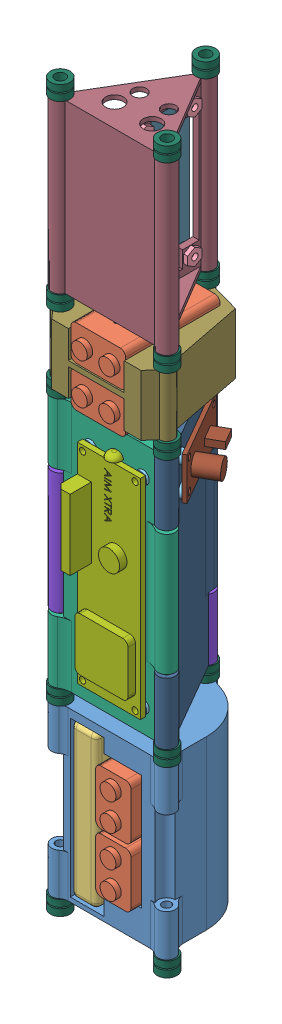
SolidWorks assembly S1B_Electronics_Bay_Avionics_Stack, configuration Default. Lengths in mm.
Overall size (104.18 344.14 103.27).
66 component instances, 15 part files, 28 mates.
Components (placement in the parent):
- S1B_Flight_Power_Stack_Assy-1: S1B_Flight_Power_Stack_Assy [Default] at (-4.2933 16.5157 -11.6983) size (58.99 80 57.67)
  - S1B_Power_Stack-1: S1B_Power_Stack [Default] at (-4.1095 89.1616 81.6309) size (58.99 80 52.18)
  - S1B_9V Battery-1: S1B_9V Battery [Default] at (-5.5953 51.787 105.8736) x (0 0 -1) z (0 -1 0) size (47.57 16.87 26.11)
  - S1B_LiPo_A1-1: S1B_LiPo_A1 [Default] at (-22.7297 11.3191 64.2994) x (0 1 0) z (0 0 -1) size (72.97 12.27 33.73)
  - S1B_9V Battery-2: S1B_9V Battery [Default] at (-5.5953 23.6758 105.8736) x (0 0 -1) z (0 -1 0) size (47.57 16.87 26.11)
- S1B_Fight_Computer_Stack_Assy-1: S1B_Fight_Computer_Stack_Assy [Default] at (37.1119 269.2904 8.8488) x (0.5 0 0.866025) z (0 -1 0) size (74.68 77.18 120)
  - S1B_6.86mm_Nut_3mm_Hole-7: S1B_6.86mm_Nut_3mm_Hole [Default] at (49.4605 62.5264 50.3494) x (0.433013 -0.75 0.5) z (-0.25 0.433013 0.866025) size (7.92 1.91 6.86)
  - S1B_6.86mm_Nut_3mm_Hole-10: S1B_6.86mm_Nut_3mm_Hole [Default] at (38.5881 85.168 145.066) x (-0.433013 0.75 -0.5) z (-0.25 0.433013 0.866025) size (7.92 1.91 6.86)
  - S1B_6.86mm_Nut_3mm_Hole-11: S1B_6.86mm_Nut_3mm_Hole [Default] at (36.9383 84.2155 50.3494) x (0.433013 -0.75 -0.5) z (0.25 -0.433013 0.866025) size (7.92 1.91 6.86)
  - S1B_6.86mm_Nut_3mm_Hole-12: S1B_6.86mm_Nut_3mm_Hole [Default] at (49.4605 62.5264 145.066) x (0.433013 -0.75 -0.5) z (0.25 -0.433013 0.866025) size (7.92 1.91 6.86)
  - S1B_Ruber_Washer_3mm-5: S1B_Ruber_Washer_3mm [Default] at (53.7083 64.9789 145.066) x (-0.5 0.866025 0) z (0 0 1) size (6 1.25 6)
  - S1B_Ruber_Washer_3mm-6: S1B_Ruber_Washer_3mm [Default] at (41.1861 86.668 145.066) x (-0.5 0.866025 0) z (0 0 1) size (6 1.25 6)
  - S1B_Ruber_Washer_3mm-7: S1B_Ruber_Washer_3mm [Default] at (53.7083 64.9789 50.3494) x (-0.5 0.866025 0) z (0 0 1) size (6 1.25 6)
  - S1B_Ruber_Washer_3mm-8: S1B_Ruber_Washer_3mm [Default] at (41.1861 86.668 50.3494) x (-0.5 0.866025 0) z (0 0 1) size (6 1.25 6)
  - S1B_Avionics_Stack - AIM-1: S1B_Avionics_Stack - AIM [Default] at (55.5493 84.6273 26.5774) x (-0.5 -0.866025 0) z (0 0 1) size (33.58 52.18 120)
  - S1B_AimXtra-1: S1B_AimXtra [Default] at (39.9161 88.8677 47.8094) x (0 0 1) z (-0.5 0.866025 0) size (102.34 16.13 30.12)
  - S1B_6.86mm_Nut_3mm_Hole-13: S1B_6.86mm_Nut_3mm_Hole [Default] at (13.2223 66.1787 125.5587) x (0.433013 0.75 -0.5) z (0.25 0.433013 0.866025) size (7.92 1.91 6.86)
  - S1B_6.86mm_Nut_3mm_Hole-14: S1B_6.86mm_Nut_3mm_Hole [Default] at (24.7223 86.0973 125.5587) x (0.433013 0.75 -0.5) z (0.25 0.433013 0.866025) size (7.92 1.91 6.86)
  - S1B_6.86mm_Nut_3mm_Hole-15: S1B_6.86mm_Nut_3mm_Hole [Default] at (13.2223 66.1787 69.0624) x (0.433013 0.75 0.5) z (-0.25 -0.433013 0.866025) size (7.92 1.91 6.86)
  - S1B_6.86mm_Nut_3mm_Hole-16: S1B_6.86mm_Nut_3mm_Hole [Default] at (24.7223 86.0973 67.5587) x (0.433013 0.75 -0.5) z (0.25 0.433013 0.866025) size (7.92 1.91 6.86)
  - S1B_Ruber_Washer_3mm-9: S1B_Ruber_Washer_3mm [Default] at (21.3404 88.0498 67.5587) x (0.5 0.866025 0) z (0 0 1) size (6 1.25 6)
  - S1B_Ruber_Washer_3mm-10: S1B_Ruber_Washer_3mm [Default] at (9.8404 68.1312 69.0624) x (0.5 0.866025 0) z (0 0 1) size (6 1.25 6)
  - S1B_Ruber_Washer_3mm-11: S1B_Ruber_Washer_3mm [Default] at (21.3404 88.0498 125.5587) x (0.5 0.866025 0) z (0 0 1) size (6 1.25 6)
  - S1B_Ruber_Washer_3mm-12: S1B_Ruber_Washer_3mm [Default] at (9.8404 68.1312 125.5587) x (0.5 0.866025 0) z (0 0 1) size (6 1.25 6)
  - S1B_Avionics_Stack-1: S1B_Avionics_Stack [Default] at (4.7361 84.6273 26.5774) size (33.58 52.18 120)
  - S1B_RBP2W-1: S1B_RBP2W [Default] at (13.9471 81.3442 101.7819) x (0 0 -1) z (0.5 0.866025 0) size (65 5.1 31.05)
  - S1B_6.86mm_Nut_3mm_Hole-17: S1B_6.86mm_Nut_3mm_Hole [Default] at (44.7248 57.1953 44.9616) x (-0.868623 0 -0.495473) z (-0.495473 0 0.868623) size (7.92 1.91 6.86)
  - S1B_6.86mm_Nut_3mm_Hole-18: S1B_6.86mm_Nut_3mm_Hole [Default] at (44.7248 57.1953 59.1316) x (-0.868623 0 -0.495473) z (-0.495473 0 0.868623) size (7.92 1.91 6.86)
  - S1B_6.86mm_Nut_3mm_Hole-19: S1B_6.86mm_Nut_3mm_Hole [Default] at (12.4948 57.1953 59.1316) x (-0.868623 0 -0.495473) z (-0.495473 0 0.868623) size (7.92 1.91 6.86)
  - S1B_6.86mm_Nut_3mm_Hole-20: S1B_6.86mm_Nut_3mm_Hole [Default] at (12.4948 57.1953 44.9616) x (-0.855922 0 -0.517105) z (-0.517105 0 0.855922) size (7.92 1.91 6.86)
  - S1B_Ruber_Washer_3mm-13: S1B_Ruber_Washer_3mm [Default] at (12.4948 52.0403 44.9616) size (6 1.25 6)
  - S1B_Ruber_Washer_3mm-14: S1B_Ruber_Washer_3mm [Default] at (44.7248 52.0403 44.9616) size (6 1.25 6)
  - S1B_Ruber_Washer_3mm-15: S1B_Ruber_Washer_3mm [Default] at (44.7248 52.0403 59.1316) size (6 1.25 6)
  - S1B_Ruber_Washer_3mm-16: S1B_Ruber_Washer_3mm [Default] at (12.4948 52.0403 59.1316) size (6 1.25 6)
  - S1B_Avionics_Stack - EasyMini-1: S1B_Avionics_Stack - EasyMini [Default] at (30.1427 40.6218 26.5774) x (-0.5 0.866025 0) z (0 0 1) size (33.58 52.18 120)
  - S1B_EZMINI-1: S1B_EZMINI [Default] at (28.7345 50.2403 46.2994) x (1 0 0) z (0 0 -1) size (38.23 12.5 21.18)
- S1B_Sensor_Power_Stack_Assy-1: S1B_Sensor_Power_Stack_Assy [Default] at (-32.7742 223.4603 27.9192) size (57.8 36.27 57.54)
  - S1B_Sensor_Power_Stack-1: S1B_Sensor_Power_Stack [Default] at (24.3714 13.7485 42.0133) size (57.8 28.96 55.69)
  - S1B_9V Battery-1: S1B_9V Battery [Default] at (37.7064 32.0365 66.7275) x (0 0 -1) z (1 0 0) size (47.57 16.87 26.11)
  - S1B_9V Battery-2: S1B_9V Battery [Default] at (37.7064 12.6309 66.7275) x (0 0 -1) z (1 0 0) size (47.57 16.87 26.11)
- S1B_Sensor_Stack_Assy-1: S1B_Sensor_Stack_Assy [Default] at (-68.238 266.8297 115.4931) x (-0.5 0 -0.866025) z (0.866025 0 -0.5) size (58.99 80 52.18)
  - S1B_Sensor_Stack_T_Mount_A2-1: S1B_Sensor_Stack_T_Mount_A2 [Default] at (9.5389 -1.0891 74.5991) size (58.99 80 52.18)
  - S1B_6.86mm_Nut_3mm_Hole-1: S1B_6.86mm_Nut_3mm_Hole [Default] at (6.8862 79.7859 74.7996) x (0.75 0.5 0.433013) z (0.433013 -0.866025 0.25) size (7.92 1.91 6.86)
  - S1B_Ruber_Washer_3mm-1: S1B_Ruber_Washer_3mm [Default] at (28.3048 79.7859 83.7015) x (0.75 -0.5 0.433013) z (0.433013 0.866025 0.25) size (6 1.25 6)
  - S1B_Ruber_Washer_3mm-2: S1B_Ruber_Washer_3mm [Default] at (8.3862 79.7859 72.2015) x (0.75 -0.5 0.433013) z (0.433013 0.866025 0.25) size (6 1.25 6)
  - S1B_Ruber_Washer_3mm-3: S1B_Ruber_Washer_3mm [Default] at (28.3048 18.0359 83.7015) x (0.75 -0.5 0.433013) z (0.433013 0.866025 0.25) size (6 1.25 6)
  - S1B_Ruber_Washer_3mm-4: S1B_Ruber_Washer_3mm [Default] at (8.3862 18.0359 72.2015) x (0.75 -0.5 0.433013) z (0.433013 0.866025 0.25) size (6 1.25 6)
  - S1B_6.86mm_Nut_3mm_Hole-3: S1B_6.86mm_Nut_3mm_Hole [Default] at (26.8048 18.0359 86.2996) x (0.75 0.5 0.433013) z (0.433013 -0.866025 0.25) size (7.92 1.91 6.86)
  - S1B_6.86mm_Nut_3mm_Hole-4: S1B_6.86mm_Nut_3mm_Hole [Default] at (6.8862 18.0359 74.7996) x (0.75 0.5 0.433013) z (0.433013 -0.866025 0.25) size (7.92 1.91 6.86)
  - S1B_6.86mm_Nut_3mm_Hole-2: S1B_6.86mm_Nut_3mm_Hole [Default] at (26.8048 79.7859 86.2996) x (0.75 0.5 0.433013) z (0.433013 -0.866025 0.25) size (7.92 1.91 6.86)
  - S1B_Sensor_PCB-1: S1B_Sensor_PCB [Default] at (32.9609 14.7859 82.637) x (0 1 0) z (0.866025 0 0.5) size (68.25 2 30)
- S1B_Blue_Damper-1: S1B_Blue_Damper [Default] at (-33.8094 18.6414 84.6011) x (0 0 -1) z (1 0 0) size (9.3 7.04 9.3)
- S1B_Blue_Damper-19: S1B_Blue_Damper [Default] at (-33.8094 105.6772 84.6011) size (9.3 7.04 9.3)
- S1B_Blue_Damper-22: S1B_Blue_Damper [Default] at (-33.8094 232.713 84.6011) size (9.3 7.04 9.3)
- S1B_Blue_Damper-25: S1B_Blue_Damper [Default] at (-33.8094 268.7048 84.6011) x (-1 0 0) z (0 0 -1) size (9.3 7.04 9.3)
- S1B_Blue_Damper-28: S1B_Blue_Damper [Default] at (-33.8094 355.7406 84.6011) size (9.3 7.04 9.3)
- S1B_Blue_Damper-29: S1B_Blue_Damper [Default] at (17.1065 355.7406 84.4952) x (-0.5 0 -0.866025) z (0.866025 0 -0.5) size (9.3 7.04 9.3)
- S1B_Blue_Damper-30: S1B_Blue_Damper [Default] at (-8.4431 355.7406 40.4537) x (-0.5 0 0.866025) z (-0.866025 0 -0.5) size (9.3 7.04 9.3)
- S1B_Blue_Damper-26: S1B_Blue_Damper [Default] at (17.1065 268.7048 84.4952) x (0.5 0 0.866025) z (-0.866025 0 0.5) size (9.3 7.04 9.3)
- S1B_Blue_Damper-27: S1B_Blue_Damper [Default] at (-8.4431 268.7048 40.4537) x (0.5 0 -0.866025) z (0.866025 0 0.5) size (9.3 7.04 9.3)
- S1B_Blue_Damper-23: S1B_Blue_Damper [Default] at (17.1065 232.713 84.4952) x (-0.5 0 -0.866025) z (0.866025 0 -0.5) size (9.3 7.04 9.3)
- S1B_Blue_Damper-24: S1B_Blue_Damper [Default] at (-8.4431 232.713 40.4537) x (-0.5 0 0.866025) z (-0.866025 0 -0.5) size (9.3 7.04 9.3)
- S1B_Blue_Damper-20: S1B_Blue_Damper [Default] at (17.1065 105.6772 84.4952) x (-0.5 0 -0.866025) z (0.866025 0 -0.5) size (9.3 7.04 9.3)
- S1B_Blue_Damper-21: S1B_Blue_Damper [Default] at (-8.4431 105.6772 40.4537) x (-0.5 0 0.866025) z (-0.866025 0 -0.5) size (9.3 7.04 9.3)
- S1B_Blue_Damper-17: S1B_Blue_Damper [Default] at (17.1065 18.6414 84.4952) x (-0.866025 0 0.5) z (-0.5 0 -0.866025) size (9.3 7.04 9.3)
- S1B_Blue_Damper-18: S1B_Blue_Damper [Default] at (-8.4431 18.6414 40.4537) x (0.866025 0 0.5) z (-0.5 0 0.866025) size (9.3 7.04 9.3)
Mates (geometry in assembly coordinates):
- Concentric2: concentric aligned: cylinder of S1B_Flight_Power_Stack_Assy-1/S1B_Power_Stack-1 through (-33.8094 25.6772 84.6011) axis (0 1 0) radius 2.0875; cylinder of S1B_Fight_Computer_Stack_Assy-1/S1B_Avionics_Stack - AIM-1 through (-33.8094 112.713 84.6011) axis (0 1 0) radius 2.0875
- Coincident1: coincident anti-aligned: cylinder of S1B_Flight_Power_Stack_Assy-1/S1B_Power_Stack-1 through (17.0038 25.6772 84.6011) axis (0 1 0) radius 2.0875; circle of Fight_Computer_Stack_Assy-1/Avionics_Stack - EasyMini-1
- Concentric3: concentric anti-aligned: cylinder of S1B_Fight_Computer_Stack_Assy-1/S1B_Avionics_Stack - AIM-1 through (-33.8094 112.713 84.6011) axis (0 1 0) radius 2.0875; cylinder of S1B_Sensor_Power_Stack_Assy-1/S1B_Sensor_Power_Stack-1 through (-33.8094 268.7048 84.6011) axis (0 -1 0) radius 1.5875
- Concentric4: concentric anti-aligned: cylinder of S1B_Fight_Computer_Stack_Assy-1/S1B_Avionics_Stack - EasyMini-1 through (17.0038 112.713 84.6011) axis (0 1 0) radius 2.0875; cylinder of S1B_Sensor_Power_Stack_Assy-1/S1B_Sensor_Power_Stack-1 through (17.0038 268.7048 84.6011) axis (0 -1 0) radius 1.5875
- Concentric5: concentric aligned: cylinder of S1B_Sensor_Power_Stack_Assy-1/S1B_Sensor_Power_Stack-1 through (-8.4028 268.7048 40.5956) axis (0 -1 0) radius 1.5875; cylinder of S1B_Sensor_Stack_Assy-1/S1B_Sensor_Stack_T_Mount_A2-1 through (-8.4028 355.7406 40.5956) axis (0 -1 0) radius 2.0875
- Concentric6: concentric aligned: cylinder of S1B_Sensor_Power_Stack_Assy-1/S1B_Sensor_Power_Stack-1 through (-33.8094 268.7048 84.6011) axis (0 -1 0) radius 1.5875; cylinder of S1B_Sensor_Stack_Assy-1/S1B_Sensor_Stack_T_Mount_A2-1 through (-33.8094 355.7406 84.6011) axis (0 -1 0) radius 2.0875
- Concentric7: concentric anti-aligned: cylinder of S1B_Flight_Power_Stack_Assy-1/S1B_Power_Stack-1 through (-33.8094 25.6772 84.6011) axis (0 1 0) radius 2.0875; cylinder of Blue_Boy-1 through (-33.8094 18.6414 84.6011) axis (0 -1 0) radius 2.5146
- Coincident2: coincident anti-aligned: plane of S1B_Flight_Power_Stack_Assy-1/S1B_Power_Stack-1 through (-8.4028 25.6772 69.9326) normal (0 -1 0); plane of Blue_Boy-1 through (-33.8094 25.6772 82.0865) normal (0 1 0)
- Parallel1: parallel anti-aligned: plane of Blue_Boy-1 through (-33.8094 18.6414 84.6011) normal (0 0 -1)
- Concentric8: concentric aligned: cylinder of Blue_Boy-1 through (-33.8094 18.6414 84.6011) axis (0 -1 0) radius 2.5146; cylinder of Blue_Boy-2 through (-33.8094 105.6772 84.6011) axis (0 -1 0) radius 2.5146
- Coincident3: coincident anti-aligned: plane of S1B_Flight_Power_Stack_Assy-1/S1B_Power_Stack-1 through (-8.4028 105.6772 69.9326) normal (0 1 0); plane of Blue_Boy-2 through (-31.2948 105.6772 84.6011) normal (0 -1 0)
- Coincident4: coincident anti-aligned: plane of S1B_Fight_Computer_Stack_Assy-1/S1B_Avionics_Stack - AIM-1 through (-8.4028 112.713 99.2696) normal (0 -1 0); plane of Blue_Boy-2 through (-31.2948 112.713 84.6011) normal (0 1 0)
- Coincident5: coincident anti-aligned: plane of S1B_Fight_Computer_Stack_Assy-1/S1B_Avionics_Stack - AIM-1 through (-8.4028 232.713 99.2696) normal (0 1 0); plane of Blue_Boy-3 through (-31.2948 232.713 84.6011) normal (0 -1 0)
- Concentric9: concentric aligned: cylinder of Blue_Boy-1 through (-33.8094 18.6414 84.6011) axis (0 -1 0) radius 2.5146; cylinder of Blue_Boy-3 through (-33.8094 232.713 84.6011) axis (0 -1 0) radius 2.5146
- Coincident6: coincident anti-aligned: plane of S1B_Sensor_Power_Stack_Assy-1/S1B_Sensor_Power_Stack-1 through (-8.4028 239.7488 69.9326) normal (0 -1 0); plane of Blue_Boy-3 through (-31.2948 239.7488 84.6011) normal (0 1 0)
- Coincident7: coincident anti-aligned: plane of S1B_Sensor_Power_Stack_Assy-1/S1B_Sensor_Power_Stack-1 through (-8.4028 268.7048 69.9326) normal (0 1 0); plane of Blue_Boy-4 through (-36.324 268.7048 84.6011) normal (0 -1 0)
- Coincident8: coincident anti-aligned: plane of Blue_Boy-4 through (-36.324 275.7406 84.6011) normal (0 1 0); plane of Blue_Boy-5 through (-36.324 268.7048 84.6011) normal (0 -1 0)
- Concentric10: concentric aligned: cylinder of Blue_Boy-1 through (-33.8094 18.6414 84.6011) axis (0 -1 0) radius 2.5146; cylinder of Blue_Boy-4 through (-33.8094 268.7048 84.6011) axis (0 -1 0) radius 2.5146
- Concentric11: concentric aligned: cylinder of Blue_Boy-4 through (-33.8094 268.7048 84.6011) axis (0 -1 0) radius 2.5146; cylinder of Blue_Boy-5 through (-33.8094 268.7048 84.6011) axis (0 -1 0) radius 2.5146
- Coincident9: coincident anti-aligned: plane of S1B_Sensor_Stack_Assy-1/S1B_Sensor_Stack_T_Mount_A2-1 through (-8.4028 275.7406 69.9326) normal (0 -1 0); plane of Blue_Boy-5 through (-36.324 275.7406 84.6011) normal (0 1 0)
- Coincident10: coincident anti-aligned: plane of S1B_Sensor_Stack_Assy-1/S1B_Sensor_Stack_T_Mount_A2-1 through (-8.4028 355.7406 69.9326) normal (0 1 0); plane of Blue_Boy-6 through (-31.2948 355.7406 84.6011) normal (0 -1 0)
- Concentric12: concentric aligned: cylinder of Blue_Boy-1 through (-33.8094 18.6414 84.6011) axis (0 -1 0) radius 2.5146; cylinder of Blue_Boy-6 through (-33.8094 355.7406 84.6011) axis (0 -1 0) radius 2.5146
- Parallel2: parallel aligned: plane of Blue_Boy-2 through (-33.8094 105.6772 84.6011) normal (1 0 0)
- Parallel3: parallel aligned: plane of Blue_Boy-3 through (-33.8094 232.713 84.6011) normal (1 0 0)
- Parallel4: parallel anti-aligned: plane of Blue_Boy-4 through (-33.8094 268.7048 84.6011) normal (-1 0 0)
- Parallel5: parallel aligned: plane of Blue_Boy-6 through (-33.8094 355.7406 84.6011) normal (1 0 0)
- Parallel6: parallel anti-aligned: plane of Blue_Boy-5 through (-33.8094 268.7048 84.6011) normal (-1 0 0)
- Coincident11: coincident anti-aligned: plane of S1B_Sensor_Power_Stack_Assy-1/S1B_Sensor_Power_Stack-1 through (-8.4028 268.7048 69.9326) normal (0 1 0); plane of Blue_Boy-5 through (-36.324 268.7048 84.6011) normal (0 -1 0)
